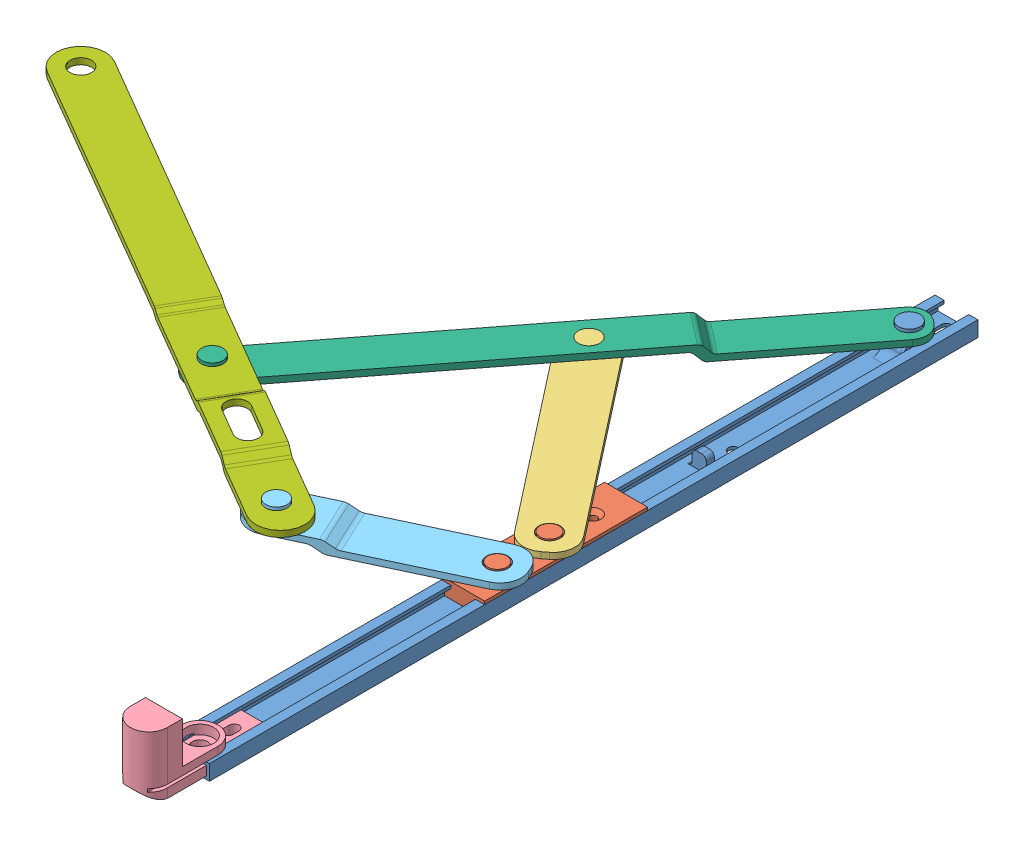
SolidWorks assembly Kinematics Project Assembly, configuration Default. Lengths in mm.
Overall size (226.94 21 268.71).
7 component instances, 7 part files, 15 mates.
Components (placement in the parent):
- Slider Runner-1: Slider Runner [Default] at (-41.5472 -4.2109 124.7847) size (14 9 250)
- Slider-1: Slider [Default] at (-41.5472 -3.2109 85.2549) x (0 0 -1) z (1 0 0) size (53 7.2 14)
- Member P-1: Member P [Default] at (-64.3395 -0.7109 28.0707) x (-0.100392 0 0.994948) z (0 1 0) size (70.3 67.98 5)
- Slider Rubber 1-2: Slider Rubber 1 [Default] at (-41.5472 -4.2109 153.4907) size (12 20 40)
- Member S-1: Member S [Default] at (-65.4952 -0.7109 85.5946) x (-0.905602 0 0.424129) z (-0.424129 0 -0.905602) size (70 7 16)
- Member Q-6: Member Q [Default] at (-91.793 -0.7109 5.1588) x (0.611558 0 -0.7912) z (0 1 0) size (175 13.04 8)
- Member L-7: Member L [Default] at (-165.7214 3.2891 53.249) x (0.864082 0 0.503352) z (-0.503352 0 0.864082) size (196 4 16)
Mates (geometry in assembly coordinates):
- Coincident7: coincident anti-aligned: plane of Slider Runner-1 through (-35.5472 -5.7109 -75.2153) normal (-1 0 0); plane of Slider-1 through (-35.5472 -5.7109 32.2549) normal (1 0 0)
- Coincident8: coincident anti-aligned: plane of Slider Runner-1 through (-37.5472 -1.7109 -75.2153) normal (0 1 0); plane of Slider-1 through (-37.5472 -1.7109 32.2549) normal (0 -1 0)
- Concentric7: concentric aligned: cylinder of Slider-1 through (-41.4432 1.4891 57.2549) axis (0 -1 0) radius 3.15; cylinder of Member 1-1 through (-41.4432 1.2891 57.2549) axis (0 -1 0) radius 3.5
- Coincident9: coincident anti-aligned: plane of Slider-1 through (-48.5472 -0.7109 32.2549) normal (0 1 0); plane of Member 1-1 through (-64.3395 -0.7109 28.0707) normal (0 -1 0)
- Concentric28: concentric aligned: cylinder of Slider Runner-1 through (-41.5472 -6.7109 170.8947) axis (0 1 0) radius 1.75; cylinder of Slider Rubber 1-2 through (-41.5472 -12.7109 170.8947) axis (0 1 0) radius 2.5
- Coincident29: coincident anti-aligned: plane of Slider Runner-1 through (-35.5472 -5.7109 -75.2153) normal (0 1 0); plane of Slider Rubber 1-2 through (-35.5472 -5.7109 193.4907) normal (0 -1 0)
- Parallel5: parallel anti-aligned: plane of Slider Runner-1 through (-35.5472 -5.7109 -75.2153) normal (-1 0 0); plane of Slider Rubber 1-2 through (-37.5472 -2.7109 193.4937) normal (1 0 0)
- Concentric41: concentric aligned: cylinder of Slider-1 through (-41.4432 1.4891 74.2549) axis (0 -1 0) radius 3.15; cylinder of Member S-1 through (-41.4432 3.2891 74.2549) axis (0 -1 0) radius 3.5
- Coincident38: coincident anti-aligned: plane of Slider-1 through (-48.5472 -0.7109 32.2549) normal (0 1 0); plane of Member S-1 through (-65.4952 -0.7109 85.5946) normal (0 -1 0)
- Concentric43: concentric aligned: cylinder of Slider Runner-1 through (-41.5472 2.2891 -59.8465) axis (0 -1 0) radius 3.5; cylinder of Member 6-6 through (-41.5472 4.2891 -59.8465) axis (0 -1 0) radius 3.5
- Coincident39: coincident anti-aligned: circle of Slider Runner-1; plane of Member 6-6 through (-41.1209 -0.7109 -59.517) normal (0 -1 0)
- Concentric44: concentric anti-aligned: cylinder of Member 1-1 through (-86.9659 4.2891 -1.0862) axis (0 1 0) radius 3.5; cylinder of Member 6-6 through (-86.9659 4.2891 -1.0862) axis (0 -1 0) radius 3.5
- Concentric45: concentric aligned: cylinder of Member S-1 through (-90.346 6.2891 97.1573) axis (0 -1 0) radius 3.5; cylinder of Member 7.2-7 through (-90.346 7.2891 97.1573) axis (0 -1 0) radius 3.5
- Concentric46: concentric aligned: cylinder of Member 6-6 through (-140.3763 7.2891 68.0132) axis (0 -1 0) radius 3.5; cylinder of Member 7.2-7 through (-140.3763 7.2891 68.0132) axis (0 -1 0) radius 3.5
- Coincident40: coincident anti-aligned: plane of Member S-1 through (-65.4952 3.2891 85.5946) normal (0 1 0); plane of Member 7.2-7 through (-242.8564 3.2891 8.3157) normal (0 -1 0)
